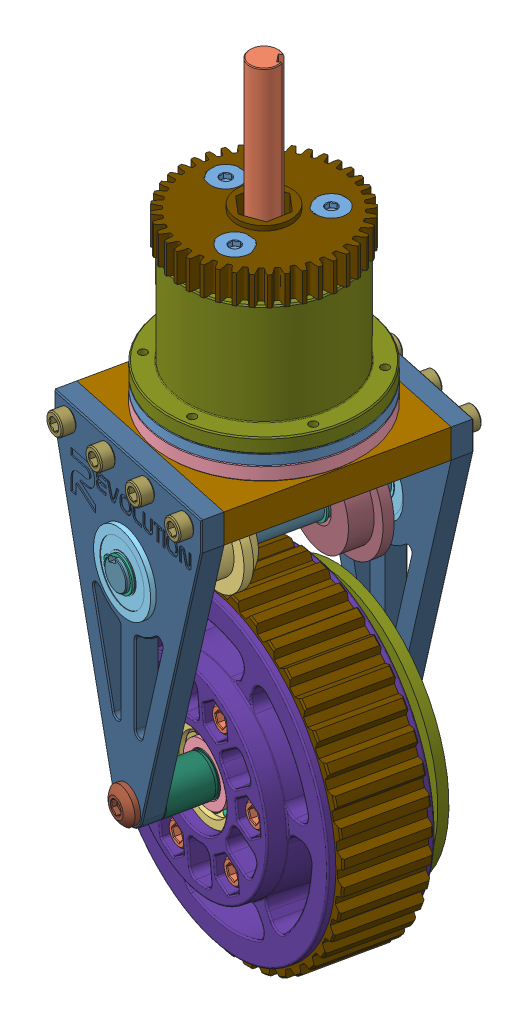
SolidWorks assembly Revolution 2 Plaction+Steering Gear, configuration Default. Lengths in mm.
Overall size (163.7 274.4 125.67).
95 component instances, 37 part files, 9 mates.
Components (placement in the parent):
- Revolution 2 Plaction-1: Revolution 2 Plaction [Default] at (62.6202 125.584 106.4116) size (163.7 274.4 125.67)
  - cs_drive_hub_asm_1-1: cs_drive_hub_asm_1 [Default] at (28.1074 158.1318 104.3172) x (-0.796969 0 0.60402) z (-0.60402 0 -0.796969) size (89.7 127.05 89.7)
    - 5906K526_thrust_bushing_1-1: 5906K526_thrust_bushing_1 [Default] at (33.9501 -89.5224 3.5116) x (-0.279506 0 -0.960144) z (0 -1 0) size (63.5 63.5 3.17)
    - cs_vert_drive_shaft_1-1: cs_vert_drive_shaft_1 [Default] at (390.5574 -784.499 -2.4616) x (0 1 0) z (0.016748 0 0.99986) size (127.05 9.26 9.53)
    - 6843K12_miter_gear_1-1: 6843K12_miter_gear_1 [Default] at (36.0118 -122.8345 2.5948) x (-0.91373 0 0.406323) z (-0.406323 0 -0.91373) size (27.69 19.05 27.69)
    - revo2_pivot_hub-1: revo2_pivot_hub [Default] at (32.6196 -72.4841 4.7196) x (-0.740355 0 0.672216) z (-0.672216 0 -0.740355) size (63.5 46.42 63.5)
    - brf-06_1-1: brf-06_1 [Default] at (33.9501 -95.4787 3.5116) x (-0.582551 0 0.812794) z (0 -1 0) size (24.59 24.59 7.11)
    - brf-06_1-2: brf-06_1 [Default] at (33.9501 -53.0226 3.5116) x (-0.999614 0 -0.027772) z (0 1 0) size (24.59 24.59 7.11)
    - Imported_1-1: Imported_1 [Default] at (33.9501 -123.279 3.5116) x (0 -1 0) z (0.051397 0 0.998678) size (0.64 12.09 10.6)
    - Imported_1-2: Imported_1 [Default] at (33.9501 -49.0094 3.5116) x (0 1 0) z (0.82628 0 -0.563259) size (0.64 12.09 10.6)
    - large_thrust_bushing_1-1: large_thrust_bushing_1 [Default] at (33.9501 -102.2097 3.5116) x (1 0 0) z (0 -1 0) size (19.05 19.05 1.57)
    - bushing_backer_1-1: bushing_backer_1 [Default] at (33.9501 -99.0347 3.5116) x (1 0 0) z (0 -1 0) size (25.4 25.4 3.17)
  - cs_wheel_box_asm_plaction-1: cs_wheel_box_asm_plaction [Default] at (-5.7354 51.1469 144.7113) x (0.977946 0 0.20886) z (0 1 0) size (149.25 84.94 179.3)
    - revo2_wheel_box_cap-1: revo2_wheel_box_cap [Default] at origin size (63.5 63.5 9.53)
    - 6843K12_miter_gear_1-1: 6843K12_miter_gear_1 [Default] at (1.3308 15.2099 -25.4535) x (-0.668029 0 0.744136) z (0.744136 0 0.668029) size (27.69 19.05 27.69)
    - revo2_side_plate-1: revo2_side_plate [Default] at (-18.57 61.2601 -1.4632) x (1 0 0) z (0 -1 0) size (63.5 106.45 6.35)
    - revo2_side_plate-2: revo2_side_plate [Default] at (18.217 -14.9399 -1.4632) x (-1 0 0) z (0 1 0) size (63.5 106.45 6.35)
    - BHCS_91255A535-1: BHCS_91255A535 [Default] at (-0.1765 -14.9399 -90.5764) x (1 0 0) z (0 -1 0) size (11.23 11.23 13.63)
    - 91251A192_shcs-1: 91251A192_shcs [Default] at (-25.5765 51.7351 4.7625) x (1 0 0) z (0 -1 0) size (6.86 6.86 13.9)
    - 91251A192_shcs-2: 91251A192_shcs [Default] at (25.2235 51.7351 4.7625) x (1 0 0) z (0 -1 0) size (6.86 6.86 13.9)
    - 91251A192_shcs-3: 91251A192_shcs [Default] at (-8.6423 51.7351 4.7665) x (1 0 0) z (0 -1 0) size (6.86 6.86 13.9)
    - 91251A192_shcs-4: 91251A192_shcs [Default] at (8.2893 -5.4149 4.7665) x (1 0 0) z (0 1 0) size (6.86 6.86 13.9)
    - 91251A192_shcs-5: 91251A192_shcs [Default] at (-25.5765 -5.4149 4.7625) x (1 0 0) z (0 1 0) size (6.86 6.86 13.9)
    - 91251A192_shcs-6: 91251A192_shcs [Default] at (25.2235 -5.4149 4.7625) x (1 0 0) z (0 1 0) size (6.86 6.86 13.9)
    - brf-06_1-1: brf-06_1 [Default] at (-0.1765 59.2789 -23.7744) x (1 0 0) z (0 1 0) size (24.59 24.59 7.11)
    - brf-06_1-2: brf-06_1 [Default] at (-0.1765 -12.9587 -23.7744) x (0.755419 0 -0.655243) z (0 -1 0) size (24.59 24.59 7.11)
    - 16t_ws_globe_gear-1: 16t_ws_globe_gear [Default] at (2.3218 39.2687 -25.5275) x (0.818565 0 -0.574414) z (0.574414 0 0.818565) size (35.31 10.29 35.31)
    - revo2_cross_drive_shaft-1: revo2_cross_drive_shaft [Default] at (136.4364 723.0009 -354.9485) x (0 -1 0) z (-0.924435 0 -0.381339) size (83.39 9.26 9.53)
    - Imported_1-1: Imported_1 [Default] at (-0.1765 -16.9719 -23.7744) x (0 1 0) z (0 0 1) size (0.64 12.09 10.6)
    - Imported_1-2: Imported_1 [Default] at (-0.1765 63.4318 -23.7744) x (0 -1 0) z (0 0 1) size (0.64 12.09 10.6)
    - large_thrust_bushing_1-1: large_thrust_bushing_1 [Default] at (-0.1765 -5.4149 -23.7744) x (1 0 0) z (0 1 0) size (19.05 19.05 1.57)
    - 91251A192_shcs-7: 91251A192_shcs [Default] at (8.2893 51.7351 4.7645) x (1 0 0) z (0 -1 0) size (6.86 6.86 13.9)
    - 91251A192_shcs-8: 91251A192_shcs [Default] at (-8.6423 -5.4149 4.7645) x (1 0 0) z (0 1 0) size (6.86 6.86 13.9)
    - Imported_1-3: Imported_1 [Default] at (-0.1765 15.6544 -23.7744) x (0 -1 0) z (0 0 1) size (0.64 12.09 10.6)
    - Imported_1-4: Imported_1 [Default] at (-0.1765 48.5474 -23.7744) x (0 -1 0) z (0 0 1) size (0.64 12.09 10.6)
    - Imported_1-5: Imported_1 [Default] at (-0.1765 37.3714 -23.7744) x (0 1 0) z (0 0 1) size (0.64 12.09 10.6)
    - BHCS_91255A535-2: BHCS_91255A535 [Default] at (-0.1765 61.2601 -90.5764) x (0.396029 0 -0.918238) z (0 1 0) size (11.23 11.23 13.63)
    - revo2_wheel_shaft-1: revo2_wheel_shaft [Default] at (-0.1765 -8.5899 -90.5764) x (0.571408 0 0.820666) z (0 1 0) size (12.7 12.7 63.5)
    - AM_36t_sprocket-1: AM_36t_sprocket [Default] at (-0.1765 48.1029 -90.5764) x (0.524782 0 0.851237) z (0 -1 0) size (82.55 82.55 3.1)
    - 4Plaction-500bearing-1: 4Plaction-500bearing [Default] at (-0.1765 3.3481 -90.5764) x (0 1 0) z (-0.599972 0 0.800021) size (41.66 115.7 115.7)
      - 4MW_d011-1: 4MW_d011 [Default] at origin size (22.87 98.05 98.05)
      - 4MW_d011-2: 4MW_d011 [Default] at (41.656 0 0) x (-1 0 0) z (0 0 -1) size (22.87 98.05 98.05)
      - 4RoughTread1-1: 4RoughTread1 [Default] at (8.128 0 0) x (0 -0.992815 0.119662) z (1 0 0) size (104 104 25.4)
      - 10-32_nylock_nut1-1: 10-32_nylock_nut1 [Default] at (130.8703 19.4882 -76.5177) x (0 -0.340837 0.940122) z (-1 0 0) size (11.68 10.93 7.15)
      - 10-32_nylock_nut1-2: 10-32_nylock_nut1 [Default] at (130.8703 76.0104 -21.3816) x (0 -0.984588 0.174888) z (-1 0 0) size (11.68 10.93 7.15)
      - 10-32_nylock_nut1-3: 10-32_nylock_nut1 [Default] at (130.8703 56.5222 55.1361) x (0 -0.643751 -0.765235) z (-1 0 0) size (11.68 10.93 7.15)
      - 10-32_nylock_nut1-4: 10-32_nylock_nut1 [Default] at (130.8703 -19.4882 76.5177) x (0 0.340837 -0.940122) z (-1 0 0) size (11.68 10.93 7.15)
      - 10-32_nylock_nut1-5: 10-32_nylock_nut1 [Default] at (130.8703 -76.0104 21.3816) x (0 0.984588 -0.174888) z (-1 0 0) size (11.68 10.93 7.15)
      - 10-32_nylock_nut1-6: 10-32_nylock_nut1 [Default] at (130.8703 -56.5222 -55.1361) x (0 0.643751 0.765235) z (-1 0 0) size (11.68 10.93 7.15)
      - 10-32x1375_shcs1-1: 10-32x1375_shcs1 [Default] at (1.5748 0 23.8125) x (0 -0.961068 -0.276312) z (0 0.276312 -0.961068) size (7.82 39.7 7.82)
      - 10-32x1375_shcs1-2: 10-32x1375_shcs1 [Default] at (1.5748 -20.6222 11.9062) x (0 -0.241241 -0.970465) z (0 0.970465 -0.241241) size (7.82 39.7 7.82)
      - 10-32x1375_shcs1-3: 10-32x1375_shcs1 [Default] at (1.5748 -20.6222 -11.9062) x (0 0.719827 -0.694154) z (0 0.694154 0.719827) size (7.82 39.7 7.82)
      - 10-32x1375_shcs1-4: 10-32x1375_shcs1 [Default] at (1.5748 0 -23.8125) x (0 0.961068 0.276312) z (0 -0.276312 0.961068) size (7.82 39.7 7.82)
      - 10-32x1375_shcs1-5: 10-32x1375_shcs1 [Default] at (1.5748 20.6222 -11.9062) x (0 0.241241 0.970465) z (0 -0.970465 0.241241) size (7.82 39.7 7.82)
      - 10-32x1375_shcs1-6: 10-32x1375_shcs1 [Default] at (1.5748 20.6222 11.9062) x (0 -0.719827 0.694154) z (0 -0.694154 -0.719827) size (7.82 39.7 7.82)
    - ball_bearing_60355K150-1: ball_bearing_60355K150 [Default] at (-0.1765 38.5271 -90.5764) x (1 0 0) z (0 1 0) size (28.57 28.57 6.35)
      - NONE-1: NONE [Default] at origin size (28.57 28.57 6.35)
      - NONEA-1: NONEA [Default] at origin size (18.68 18.68 6.35)
      - NONEB-1: NONEB [Default] at origin size (3.43 3.43 3.43)
      - NONEC-1: NONEC [Default] at origin size (3.43 3.43 3.43)
      - NONED-1: NONED [Default] at origin size (3.43 3.43 3.43)
      - NONEE-1: NONEE [Default] at origin size (3.43 3.43 3.43)
      - NONEF-1: NONEF [Default] at origin size (3.43 3.43 3.43)
      - NONEG-1: NONEG [Default] at origin size (3.43 3.43 3.43)
      - NONEH-1: NONEH [Default] at origin size (3.43 3.43 3.43)
      - NONEI-1: NONEI [Default] at origin size (3.43 3.43 3.43)
      - NONEJ-1: NONEJ [Default] at origin size (3.43 3.43 3.43)
      - NONEK-1: NONEK [Default] at origin size (3.43 3.43 3.43)
    - ball_bearing_60355K150-2: ball_bearing_60355K150 [Default] at (-0.1765 9.8251 -90.5764) x (1 0 0) z (0 1 0) size (28.57 28.57 6.35)
      - NONE-1: NONE [Default] at origin size (28.57 28.57 6.35)
      - NONEA-1: NONEA [Default] at origin size (18.68 18.68 6.35)
      - NONEB-1: NONEB [Default] at origin size (3.43 3.43 3.43)
      - NONEC-1: NONEC [Default] at origin size (3.43 3.43 3.43)
      - NONED-1: NONED [Default] at origin size (3.43 3.43 3.43)
      - NONEE-1: NONEE [Default] at origin size (3.43 3.43 3.43)
      - NONEF-1: NONEF [Default] at origin size (3.43 3.43 3.43)
      - NONEG-1: NONEG [Default] at origin size (3.43 3.43 3.43)
      - NONEH-1: NONEH [Default] at origin size (3.43 3.43 3.43)
      - NONEI-1: NONEI [Default] at origin size (3.43 3.43 3.43)
      - NONEJ-1: NONEJ [Default] at origin size (3.43 3.43 3.43)
      - NONEK-1: NONEK [Default] at origin size (3.43 3.43 3.43)
    - bushing_backer_1-1: bushing_backer_1 [Default] at (-0.1765 -5.4149 -23.7744) x (1 0 0) z (0 -1 0) size (25.4 25.4 3.17)
    - 90128A218-1: 90128A218 [Default] at (-22.1736 35.8601 14.097) size (7.92 7.92 14.58)
    - 90128A218-2: 90128A218 [Default] at (-22.1736 10.4601 14.097) x (0.5 0.866025 0) z (0 0 1) size (7.92 7.92 14.58)
    - 90128A218-3: 90128A218 [Default] at (-0.1765 -2.2399 14.097) x (-0.5 0.866025 0) z (0 0 1) size (7.92 7.92 14.58)
    - 90128A218-4: 90128A218 [Default] at (21.8205 10.4601 14.097) x (-1 0 0) z (0 0 1) size (7.92 7.92 14.58)
    - 90128A218-5: 90128A218 [Default] at (21.8205 35.8601 14.097) x (-0.5 -0.866025 0) z (0 0 1) size (7.92 7.92 14.58)
    - 90128A218-6: 90128A218 [Default] at (-0.1765 48.5601 14.097) x (0.5 -0.866025 0) z (0 0 1) size (7.92 7.92 14.58)
  - bushing_hub_asm_1-1: bushing_hub_asm_1 [Default] at (11.3553 106.7094 120.0903) x (0.988095 0 -0.153847) z (-0.153847 0 -0.988095) size (63.5 38.1 63.5)
    - revo2_steering_hub_1-1: revo2_steering_hub_1 [Default] at origin size (63.5 38.1 63.5)
    - 1_1-1: 1_1 [Default] at (-0.595 0 0) size (44.45 38.1 44.45)
- 40 Tooth Steering Gear+Mounting Holes-2: 40 Tooth Steering Gear+Mounting Holes [default] at (61.5494 237.4369 228.4366) x (0.982925 0 0.184009) z (0 1 0) size (53.25 53.25 11.09)
- fhcs_91253A238-2: fhcs_91253A238 [Default] at (71.8811 238.9736 216.3838) x (1 0 0) z (0 1 0) size (10.32 10.32 6.54)
- fhcs_91253A238-3: fhcs_91253A238 [Default] at (66.8216 238.9736 243.4106) x (1 0 0) z (0 1 0) size (10.32 10.32 6.54)
- fhcs_91253A238-4: fhcs_91253A238 [Default] at (45.9455 238.9736 225.5155) x (1 0 0) z (0 1 0) size (10.32 10.32 6.54)
Mates (geometry in assembly coordinates):
- Coincident2: coincident anti-aligned: plane of Revolution 2 Plaction-1/cs_drive_hub_asm_1-1/revo2_pivot_hub-1 through (63.3021 232.6744 219.0742) normal (0 1 0); plane of 40 Tooth Steering Gear+Mounting Holes-2 through (85.1763 232.6744 225.3694) normal (0 -1 0)
- Concentric15: concentric aligned: circle of Revolution 2 Plaction-1/cs_drive_hub_asm_1-1/cs_vert_drive_shaft_1-1; circle of 40 Tooth Steering Gear+Mounting Holes-2
- Concentric16: concentric anti-aligned: circle of Revolution 2 Plaction-1/cs_drive_hub_asm_1-1/revo2_pivot_hub-1; circle of 40 Tooth Steering Gear+Mounting Holes-2
- Concentric18: concentric anti-aligned: cylinder of 40 Tooth Steering Gear+Mounting Holes-2 through (71.8811 242.1994 216.3838) axis (0 1 0) radius 2.5527; circle of fhcs_91253A238-2
- Coincident4: coincident aligned: plane of 40 Tooth Steering Gear+Mounting Holes-2 through (85.1763 242.1994 225.3694) normal (0 1 0); plane of fhcs_91253A238-2 through (71.8811 242.1994 216.3838) normal (0 1 0)
- Concentric19: concentric aligned: cylinder of 40 Tooth Steering Gear+Mounting Holes-2 through (66.8216 242.1994 243.4106) axis (0 1 0) radius 2.5527; circle of fhcs_91253A238-3
- Coincident5: coincident aligned: plane of 40 Tooth Steering Gear+Mounting Holes-2 through (85.1763 242.1994 225.3694) normal (0 1 0); plane of fhcs_91253A238-3 through (66.8216 242.1994 243.4106) normal (0 1 0)
- Concentric20: concentric aligned: cylinder of 40 Tooth Steering Gear+Mounting Holes-2 through (45.9455 242.1994 225.5155) axis (0 1 0) radius 2.5527; circle of fhcs_91253A238-4
- Coincident6: coincident aligned: plane of 40 Tooth Steering Gear+Mounting Holes-2 through (85.1763 242.1994 225.3694) normal (0 1 0); plane of fhcs_91253A238-4 through (45.9455 242.1994 225.5155) normal (0 1 0)
